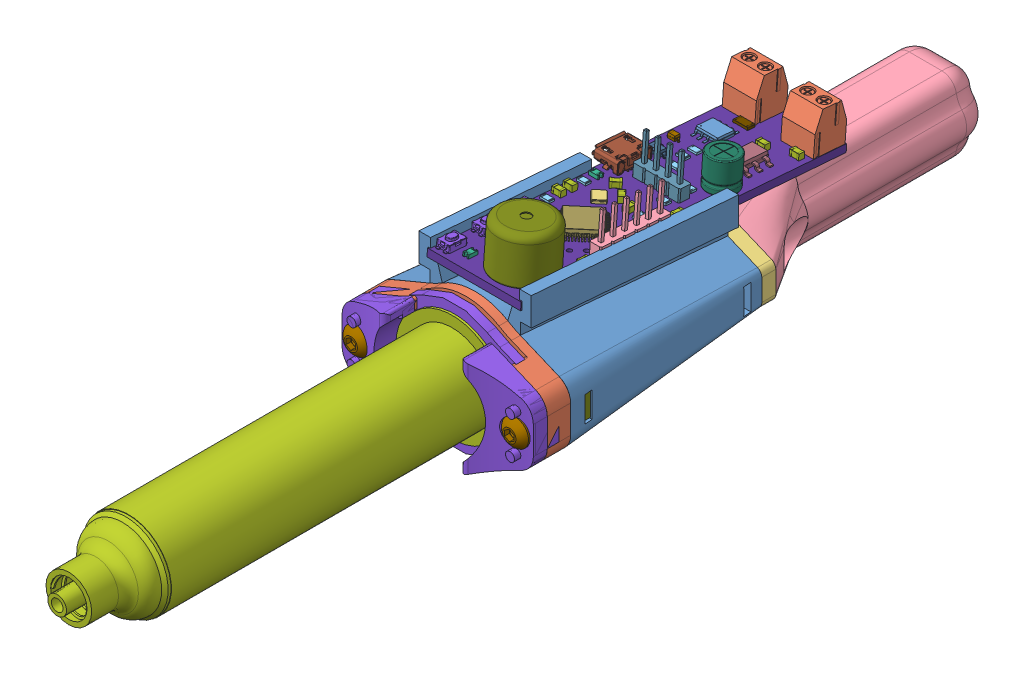
SolidWorks assembly SolderPasteMotor, configuration Default. Lengths in mm.
Overall size (41.01 39.67 192.57).
112 component instances, 35 part files, 50 mates.
Components (placement in the parent):
- ShaftCover-2: ShaftCover [Default] x (-1 0 0) z (0 0 -1) size (41.01 32.28 44.71)
- SyringeFixtureLockFlat-1: SyringeFixtureLockFlat [Default] at (0 0 2.5) size (41 27 7)
- ShaftMountFlat-1: ShaftMountFlat [Default] at (-78.4823 18.1365 -47.5) x (-1 0 0) z (0 0 1) size (34 20 3)
- TopCover-1: TopCover [Default] at (0 0 -47.5) x (1 0 0) z (0 0 -1) size (34.13 20.02 55.59)
- Piston-1: Piston [Default] at (0 0 -37.1906) size (11.9 11.9 56.85)
- Matice M4-1: Matice M4 [Matice M4] at (0 0 -23.8906) x (0.866025 -0.5 0) z (0 0 1) size (7 8.08 3.2)
- Syringe-1: Syringe [Default] at (0 0 1.9) size (30 23 87.7)
- SyringeFixtureTube-2: SyringeFixtureTube [Default] at (0 0 5) size (41 27 9.14)
- SyringeFixtureTube-3: SyringeFixtureTube [Default] at (0 0 5) x (-1 0 0) z (0 0 1) size (41 27 9.14)
- SroubM3x16pulkulata-1: SroubM3x16pulkulata [SroubM3x16pulkulata] at (17 0 9.65) x (0 0 -1) z (1 0 0) size (17.65 5.7 5.7)
- SroubM3x16pulkulata-2: SroubM3x16pulkulata [SroubM3x16pulkulata] at (-17 0 9.65) x (0 0 -1) z (1 0 0) size (17.65 5.7 5.7)
- SroubM3x16pulkulata-3: SroubM3x16pulkulata [SroubM3x16pulkulata] at (12 0 -50.65) x (0 0 1) z (-1 0 0) size (17.65 5.7 5.7)
- SroubM3x16pulkulata-4: SroubM3x16pulkulata [SroubM3x16pulkulata] at (-12 0 -50.65) x (0 0 1) z (-1 0 0) size (17.65 5.7 5.7)
- PistonHolder-1: PistonHolder [Default] at (0 0 11.3094) x (-0.337663 -0.941267 0) z (0 0 1) size (15 15 34.7)
- SyringePiston-1: SyringePiston [Default] at (0 0 30.4574) x (-0.941267 0.337663 0) z (0 0 1) size (15.7 15.7 17.5)
- MotorGearBox-1: MotorGearBox [Default] at (0 0 -95.3) x (0 -1 0) z (0 0 1) size (12.05 11.9 84.89) (flexible)
  - Motor-1: Motor [Default] at origin size (12 10 32.2)
  - GearBox-1: GearBox [Default] at (0 0 14) size (12.05 10.05 9.8)
  - Coupling-1: Coupling [Default] at (0 0 23.8) x (0.380785 0.924664 0) z (0 0 1) size (9 9 20)
  - ThreadRod-1: ThreadRod [Default] at (0 0 33.8) x (0.380785 0.924664 0) z (0 0 1) size (4.06 4.64 71.05)
- Matice M3 Ctverec-1: Matice M3 Ctverec [Default] at (17 0 -5.3) size (5.5 5.5 2)
- Matice M3 Ctverec-2: Matice M3 Ctverec [Default] at (-17 0 -3.3) x (-1 0 0) z (0 0 -1) size (5.5 5.5 2)
- Matice M3 Ctverec-3: Matice M3 Ctverec [Default] at (12 0 -42) size (5.5 5.5 2)
- Matice M3 Ctverec-4: Matice M3 Ctverec [Default] at (-12 0 -40) x (-1 0 0) z (0 0 -1) size (5.5 5.5 2)
- AxialniLozisko_F4-10_10x4x4-1: AxialniLozisko_F4-10_10x4x4 [AxialniLozisko_F6-12_12x6x4.5] at (0 0 -49.5) x (0 0 -1) z (0.989026 -0.147744 0) size (4 10 10)
- AxialniLozisko_F4-10_10x4x4-3: AxialniLozisko_F4-10_10x4x4 [AxialniLozisko_F6-12_12x6x4.5] at (0 0 -42.5) x (0 0 -1) z (0.966633 0.256167 0) size (4 10 10)
- Matice M4-2: Matice M4 [Matice M4] at (0 0 -37.3) x (0.702576 -0.711608 0) z (0 0 1) size (7 8.08 3.2)
- SPD_DC_MotorHBridge-1: SPD_DC_MotorHBridge [Default] at (-10.016 15.0227 0.2892) x (0 -0.078408 -0.996921) z (0 0.996921 -0.078408) size (70.04 21.75 12.53)
  - SPD_DC_MotorHBridge.step-1: SPD_DC_MotorHBridge.step [Default] at origin size (70.04 21.75 12.53)
    - R_1206_3216Metric.step-1: R_1206_3216Metric.step [Default] at (61.7855 -6.223 1.65) x (0 -1 0) z (0 0 1) size (3.2 1.6 0.55)
      - SOLID.step-1: SOLID.step [Default] at origin size (3.2 1.6 0.55)
    - HSOP-8-1EP_3.9x4.9mm_P1.27mm_EP2.41x3.1mm.step-1: HSOP-8-1EP_3.9x4.9mm_P1.27mm_EP2.41x3.1mm.step [Default] at (56.515 -5.2705 1.65) size (6.3 4.9 1.1)
      - SOLID-0.step-1: SOLID-0.step [Default] at origin size (6.3 4.9 1.1)
    - Screw_Terminal_Block_3.5mm_Blue_2-way.step-1: Screw_Terminal_Block_3.5mm_Blue_2-way.step [Default] at (66.294 -3.965 1.65) x (0 1 0) z (1 0 0) size (7.3 10.4 6.8)
      - COMPOUND.step-1: COMPOUND.step [Default] at origin size (7.3 10.4 6.8)
    - Crystal_SMD_SeikoEpson_TSX3225-4Pin_3.2x2.5mm_HandSoldering.step-1: Crystal_SMD_SeikoEpson_TSX3225-4Pin_3.2x2.5mm_HandSoldering.step [Default] at (29.972 -6.858 1.65) x (0.707107 0.707107 0) z (0 0 1) size (3.2 2.5 0.64)
      - SOLID-1.step-1: SOLID-1.step [Default] at origin size (3.2 2.5 0.64)
    - PinHeader_1x06_P2.54mm_Vertical.step-1: PinHeader_1x06_P2.54mm_Vertical.step [Default] at (31.242 -18.4912 1.65) x (0 -1 0) z (0 0 1) size (2.54 15.24 11.54)
      - SOLID-2.step-1: SOLID-2.step [Default] at origin size (2.54 15.24 11.54)
    - R_0805_2012Metric.step-1: R_0805_2012Metric.step [Default] at (31.496 -2.0828 1.65) x (0 1 0) z (0 0 1) size (2 1.2 0.45)
      - SOLID-3.step-1: SOLID-3.step [Default] at origin size (2 1.2 0.45)
    - D_0805_2012Metric.step-1: D_0805_2012Metric.step [Default] at (34.1376 -2.0828 1.65) x (0 1 0) z (0 0 1) size (2 1.27 0.8)
      - SOLID-4.step-1: SOLID-4.step [Default] at origin size (2 1.27 0.8)
    - R_0805_2012Metric.step-2: R_0805_2012Metric.step [Default] at (8.2804 -5.7912 1.65) x (-1 0 0) z (0 0 1) size (2 1.2 0.45)
      - SOLID-3.step-1: SOLID-3.step [Default] at origin size (2 1.2 0.45)
    - D_0805_2012Metric.step-2: D_0805_2012Metric.step [Default] at (3.4036 -5.7404 1.65) size (2 1.27 0.8)
      - SOLID-4.step-1: SOLID-4.step [Default] at origin size (2 1.27 0.8)
    - R_0805_2012Metric.step-3: R_0805_2012Metric.step [Default] at (23.622 -2.0828 1.65) x (0 -1 0) z (0 0 1) size (2 1.2 0.45)
      - SOLID-3.step-1: SOLID-3.step [Default] at origin size (2 1.2 0.45)
    - R_0805_2012Metric.step-4: R_0805_2012Metric.step [Default] at (42.5196 -8.0264 1.65) x (0 1 0) z (0 0 1) size (2 1.2 0.45)
      - SOLID-3.step-1: SOLID-3.step [Default] at origin size (2 1.2 0.45)
    - R_0805_2012Metric.step-5: R_0805_2012Metric.step [Default] at (45.1612 -8.0264 1.65) x (0 1 0) z (0 0 1) size (2 1.2 0.45)
      - SOLID-3.step-1: SOLID-3.step [Default] at origin size (2 1.2 0.45)
    - R_0805_2012Metric.step-6: R_0805_2012Metric.step [Default] at (42.2656 -13.97 1.65) x (0 1 0) z (0 0 1) size (2 1.2 0.45)
      - SOLID-3.step-1: SOLID-3.step [Default] at origin size (2 1.2 0.45)
    - R_0805_2012Metric.step-7: R_0805_2012Metric.step [Default] at (36.83 -13.97 1.65) x (0 1 0) z (0 0 1) size (2 1.2 0.45)
      - SOLID-3.step-1: SOLID-3.step [Default] at origin size (2 1.2 0.45)
    - R_0805_2012Metric.step-8: R_0805_2012Metric.step [Default] at (30.8864 -14.6812 1.65) size (2 1.2 0.45)
      - SOLID-3.step-1: SOLID-3.step [Default] at origin size (2 1.2 0.45)
    - R_0805_2012Metric.step-9: R_0805_2012Metric.step [Default] at (15.0876 -11.1252 1.65) x (0 -1 0) z (0 0 1) size (2 1.2 0.45)
      - SOLID-3.step-1: SOLID-3.step [Default] at origin size (2 1.2 0.45)
    - R_0805_2012Metric.step-10: R_0805_2012Metric.step [Default] at (50.6476 -6.8072 1.65) x (0 1 0) z (0 0 1) size (2 1.2 0.45)
      - SOLID-3.step-1: SOLID-3.step [Default] at origin size (2 1.2 0.45)
    - R_0805_2012Metric.step-11: R_0805_2012Metric.step [Default] at (48.1584 -6.7564 1.65) x (0 -1 0) z (0 0 1) size (2 1.2 0.45)
      - SOLID-3.step-1: SOLID-3.step [Default] at origin size (2 1.2 0.45)
    - C_0805_2012Metric.step-1: C_0805_2012Metric.step [Default] at (26.1112 -2.0828 1.65) x (0 -1 0) z (0 0 1) size (2 1.25 1.25)
      - SOLID-5.step-1: SOLID-5.step [Default] at origin size (2 1.25 1.25)
    - C_0805_2012Metric.step-2: C_0805_2012Metric.step [Default] at (28.5496 -2.0828 1.65) x (0 -1 0) z (0 0 1) size (2 1.25 1.25)
      - SOLID-5.step-1: SOLID-5.step [Default] at origin size (2 1.25 1.25)
    - C_0805_2012Metric.step-3: C_0805_2012Metric.step [Default] at (30.9372 -12.446 1.65) size (2 1.25 1.25)
      - SOLID-5.step-1: SOLID-5.step [Default] at origin size (2 1.25 1.25)
    - C_0805_2012Metric.step-4: C_0805_2012Metric.step [Default] at (15.0876 -6.8072 1.65) x (0 1 0) z (0 0 1) size (2 1.25 1.25)
      - SOLID-5.step-1: SOLID-5.step [Default] at origin size (2 1.25 1.25)
    - C_0805_2012Metric.step-5: C_0805_2012Metric.step [Default] at (59.2836 -12.7508 1.65) x (0 -1 0) z (0 0 1) size (2 1.25 1.25)
      - SOLID-5.step-1: SOLID-5.step [Default] at origin size (2 1.25 1.25)
    - C_0805_2012Metric.step-6: C_0805_2012Metric.step [Default] at (35.2552 -18.4912 1.65) size (2 1.25 1.25)
      - SOLID-5.step-1: SOLID-5.step [Default] at origin size (2 1.25 1.25)
    - C_0805_2012Metric.step-7: C_0805_2012Metric.step [Default] at (61.4172 -17.9324 1.65) x (0 1 0) z (0 0 1) size (2 1.25 1.25)
      - SOLID-5.step-1: SOLID-5.step [Default] at origin size (2 1.25 1.25)
    - C_0805_2012Metric.step-8: C_0805_2012Metric.step [Default] at (14.6304 -18.8468 1.65) x (-1 0 0) z (0 0 1) size (2 1.25 1.25)
      - SOLID-5.step-1: SOLID-5.step [Default] at origin size (2 1.25 1.25)
    - C_0805_2012Metric.step-9: C_0805_2012Metric.step [Default] at (34.29 -6.096 1.65) x (0.707107 -0.707107 0) z (0 0 1) size (2 1.25 1.25)
      - SOLID-5.step-1: SOLID-5.step [Default] at origin size (2 1.25 1.25)
    - C_0805_2012Metric.step-10: C_0805_2012Metric.step [Default] at (32.258 -9.398 1.65) x (0.707107 0.707107 0) z (0 0 1) size (2 1.25 1.25)
      - SOLID-5.step-1: SOLID-5.step [Default] at origin size (2 1.25 1.25)
    - KMR231NGLFS.step-1: KMR231NGLFS.step [Default] at (3.1496 -1.9685 1.65) x (-1 0 0) z (0 1 0) size (4.6 1.92 2.8)
      - SOLID-6.step-1: SOLID-6.step [Default] at origin size (4.6 1.92 2.8)
    - KMR231NGLFS.step-2: KMR231NGLFS.step [Default] at (10.7188 -1.9812 1.65) x (-1 0 0) z (0 1 0) size (4.6 1.92 2.8)
      - SOLID-6.step-1: SOLID-6.step [Default] at origin size (4.6 1.92 2.8)
    - KMR231NGLFS.step-3: KMR231NGLFS.step [Default] at (18.2372 -1.9812 1.65) x (-1 0 0) z (0 1 0) size (4.6 1.92 2.8)
      - SOLID-6.step-1: SOLID-6.step [Default] at origin size (4.6 1.92 2.8)
    - D_SOD-323.step-1: D_SOD-323.step [Default] at (49.53 -11.43 1.65) x (0 1 0) z (0 0 1) size (2.5 1.25 1.1)
      - SOLID-7.step-1: SOLID-7.step [Default] at origin size (2.5 1.25 1.1)
    - D_SOD-323.step-2: D_SOD-323.step [Default] at (50.673 -2.2225 1.65) x (0 -1 0) z (0 0 1) size (2.5 1.25 1.1)
      - SOLID-7.step-1: SOLID-7.step [Default] at origin size (2.5 1.25 1.1)
    - D_SOD-123.step-1: D_SOD-123.step [Default] at (45.8724 -3.4036 1.65) x (0 -1 0) z (0 0 1) size (3.8 1.6 1.25)
      - SOLID-8.step-1: SOLID-8.step [Default] at origin size (3.8 1.6 1.25)
    - USB_Micro-B_Amphenol_10118193-0001LF_Horizontal.step-1: USB_Micro-B_Amphenol_10118193-0001LF_Horizontal.step [Default] at (138.1935 -4.547 1.3) x (-1 0 0) z (0 1 0) size (7.87 3.61 5.71)
      - COMPOUND-9.step-1: COMPOUND-9.step [Default] at origin size (7.87 3.61 5.71)
    - LQFP-48_7x7mm_P0.5mm.step-1: LQFP-48_7x7mm_P0.5mm.step [Default] at (22.5552 -10.9855 1.65) x (-0.707107 -0.707107 0) z (0 0 1) size (9 9 1.5)
      - SOLID-10.step-1: SOLID-10.step [Default] at origin size (9 9 1.5)
    - Screw_Terminal_Block_3.5mm_Blue_2-way.step-2: Screw_Terminal_Block_3.5mm_Blue_2-way.step [Default] at (66.294 -16.538 1.65) x (0 1 0) z (1 0 0) size (7.3 10.4 6.8)
      - COMPOUND.step-1: COMPOUND.step [Default] at origin size (7.3 10.4 6.8)
    - SOT-223.step-1: SOT-223.step [Default] at (54.2036 -13.97 1.65) x (0 1 0) z (0 0 1) size (7 6.5 1.7)
      - SOLID-11.step-1: SOLID-11.step [Default] at origin size (7 6.5 1.7)
    - PinHeader_1x04_P2.54mm_Vertical.step-1: PinHeader_1x04_P2.54mm_Vertical.step [Default] at (39.5224 -14.478 1.65) x (-1 0 0) z (0 0 1) size (2.54 10.16 11.54)
      - SOLID-12.step-1: SOLID-12.step [Default] at origin size (2.54 10.16 11.54)
    - CP_Radial_D6.3mm_P2.50mm.step-1: CP_Radial_D6.3mm_P2.50mm.step [Default] at (45.5568 -16.3576 1.65) size (7.78 8.05 8.3)
      - SOLID-13.step-1: SOLID-13.step [Default] at origin size (7.78 8.05 8.3)
    - Buzzer_12x9.5RM7.6.step-1: Buzzer_12x9.5RM7.6.step [Default] at (10.668 -13.589 1.65) x (-1 0 0) z (0 0 1) size (12 12 12.53)
      - SOLID-14.step-1: SOLID-14.step [Default] at origin size (12 12 12.53)
    - COMPOUND-15.step-1: COMPOUND-15.step [Default] at origin size (70.04 20.07 1.6)
Mates (geometry in assembly coordinates):
- Rovnoběžná1: parallel anti-aligned: plane of Piston-1 through (2.0207 3.5 -23.8906) normal (-0.866025 -0.5 0); plane of Matice M4-1 through (4.0415 0 -27.0906) normal (0.866025 0.5 0)
- Sjednocená9: coincident anti-aligned: plane of Piston-1 through (0 0 -23.8906) normal (0 0 -1); plane of Matice M4-1 through (-6.0622 3.5 -23.8906) normal (0 0 1)
- Sjednocená11: coincident anti-aligned: plane of SyringeFixtureLockFlat-1 through (16.5 -2.982 0) normal (0 0 -1); plane of ShaftCover-2 through (16.5 3 0) normal (0 0 1)
- Soustředná164: concentric aligned: cylinder of ShaftMountFlat-1 through (0 0 -47.5) axis (0 0 1) radius 2.25; cylinder of ShaftCover-2 through (0 0 -14) axis (0 0 1) radius 8.75
- Soustředná165: concentric anti-aligned: cylinder of ShaftMountFlat-1 through (12 0 -47.5) axis (0 0 1) radius 1.8; cylinder of ShaftCover-2 through (12 0 -29.5) axis (0 0 -1) radius 1.8
- Sjednocená12: coincident anti-aligned: plane of ShaftMountFlat-1 through (0 0 -44.5) normal (0 0 1); plane of ShaftCover-2 through (0 0 -44.5) normal (0 0 -1)
- Sjednocená13: coincident anti-aligned: plane of ShaftMountFlat-1 through (0 0 -47.5) normal (0 0 -1); plane of TopCover-1 through (0 0 -47.5) normal (0 0 1)
- Soustředná167: concentric aligned: cylinder of ShaftMountFlat-1 through (12 0 -47.5) axis (0 0 1) radius 1.8; cylinder of TopCover-1 through (12 0 -96.5098) axis (0 0 1) radius 1.8
- Sjednocená14: coincident anti-aligned: plane of SyringeFixtureLockFlat-1 through (0 0 1.9) normal (0 0 1); plane of Syringe-1 through (9.3374 -9.75 1.9) normal (0 0 -1)
- Soustředná169: concentric anti-aligned: cylinder of ShaftCover-2 through (0 0 -14) axis (0 0 1) radius 8.75; cylinder of Syringe-1 through (0 0 74.3) axis (0 0 -1) radius 9.2
- Soustředná175: concentric anti-aligned: cylinder of ShaftCover-2 through (17 0 -14) axis (0 0 1) radius 1.8; cylinder of SyringeFixtureLockFlat-1 through (17 0 5) axis (0 0 -1) radius 1.8
- Soustředná176: concentric anti-aligned: cylinder of ShaftCover-2 through (-17 0 -14) axis (0 0 1) radius 1.8; cylinder of SyringeFixtureLockFlat-1 through (-17 0 5) axis (0 0 -1) radius 1.8
- Soustředná178: concentric aligned: cylinder of ShaftMountFlat-1 through (-12 0 -47.5) axis (0 0 1) radius 1.8; cylinder of TopCover-1 through (-12 0 -96.5098) axis (0 0 1) radius 1.8
- Mezní úhel1: limit planar angle = 0 rad anti-aligned: plane of Syringe-1 through (9.3374 -7.75 4.9) normal (0 -1 0); plane of SyringeFixtureLockFlat-1 through (9.3374 -7.75 1.9) normal (0 1 0)
- Sjednocená16: coincident anti-aligned: plane of SyringeFixtureLockFlat-1 through (16.5 -2.982 5) normal (0 0 1); plane of SyringeFixtureTube-2 through (16.5 2.982 5) normal (0 0 -1)
- Soustředná179: concentric aligned: cylinder of SyringeFixtureLockFlat-1 through (17 0 5) axis (0 0 -1) radius 1.8; cylinder of SyringeFixtureTube-2 through (17 0 12) axis (0 0 -1) radius 1.8
- Soustředná1821: concentric anti-aligned: cylinder of SyringeFixtureTube-2 through (17 0 12) axis (0 0 -1) radius 1.8; cylinder of SroubM3x16pulkulata-1 through (17 0 9.65) axis (0 0 1) radius 2.85
- Sjednocená241: coincident anti-aligned: plane of SyringeFixtureTube-2 through (17 0 8) normal (0 0 1); plane of SroubM3x16pulkulata-1 through (17 1.5 8) normal (0 0 -1)
- Soustředná1831: concentric aligned: cylinder of TopCover-1 through (12 0 -49) axis (0 0 -1) radius 3; cylinder of SroubM3x16pulkulata-3 through (12 0 -50.65) axis (0 0 -1) radius 2.85
- Sjednocená251: coincident anti-aligned: plane of TopCover-1 through (12 0 -49) normal (0 0 -1); plane of SroubM3x16pulkulata-3 through (12 1.5 -49) normal (0 0 1)
- Soustředná185: concentric anti-aligned: cylinder of PistonHolder-1 through (0 0 11.3094) axis (0 0 1) radius 2.1; cylinder of SyringePiston-1 through (0 0 47.9584) axis (0 0 -1) radius 1
- Rovnoběžná4: parallel anti-aligned: plane of PistonHolder-1 through (-0.4834 0.5984 39.4594) normal (-0.337663 -0.941267 0); plane of SyringePiston-1 through (0.1351 0.3765 47.9594) normal (0.337663 0.941267 0)
- Sjednocená28: coincident aligned: circle of PistonHolder-1; circle of SyringePiston-1
- Sjednocená30: coincident aligned: plane of SyringeFixtureLockFlat-1 through (20.5 3 5) normal (1 0 0); plane of SyringeFixtureTube-2 through (20.5 3 12) normal (1 0 0)
- Mezní vzdálenost3: limit distance = 38.6426 mm aligned: plane of Syringe-1 through (-4.9 0 78.1) normal (0 0 -1); plane of SyringePiston-1 through (0 0 39.4574) normal (0 0 -1)
- Rovnoběžná6: parallel anti-aligned: plane of SyringeFixtureLockFlat-1 through (-4.65 6.2 0) normal (0 -1 0); plane of Piston-1 through (5 5.95 11.3094) normal (0 1 0)
- Šroub1: screw = 1.5 mm anti-aligned: cylinder of Piston-1 through (0 0 11.3094) axis (0 0 -1) radius 7.5; circle of PistonHolder-1
- Vystředění3: width anti-aligned: plane of TopCover-1 through (-5.25 -6.25 -97) normal (1 0 0); plane of TopCover-1 through (5.25 -6.25 -97) normal (-1 0 0); plane of MotorGearBox-1/Motor-1 through (-5 3.35 -81.3) normal (-1 0 0); plane of MotorGearBox-1/Motor-1 through (5 3.35 -81.3) normal (1 0 0)
- Vystředění4: width anti-aligned: plane of TopCover-1 through (5.25 6.25 -97) normal (0 -1 0); plane of TopCover-1 through (5.25 -6.25 -97) normal (0 1 0); plane of MotorGearBox-1/GearBox-1 through (5.025 6.025 -72.3) normal (0 1 0); plane of MotorGearBox-1/GearBox-1 through (5.025 -6.025 -72.3) normal (0 -1 0)
- Soustředná1832: concentric aligned: cylinder of Piston-1 through (0 0 -16.298) axis (0 0 -1) radius 2.4; cylinder of MotorGearBox-1/Coupling-1 through (0 0 -51.5) axis (0 0 -1) radius 4.5
- Šroub2: screw = 0.7 anti-aligned: cylinder of PistonHolder-1 through (0 0 46.3094) axis (0 0 -1) radius 7.5; circle of MotorGearBox-1/ThreadRod-1
- Sjednocená253: coincident anti-aligned: plane of Piston-1 through (0 0 11.3094) normal (0 0 1); plane of PistonHolder-1 through (0 0 11.3094) normal (0 0 -1)
- Soustředná1833: concentric aligned: cylinder of ShaftCover-2 through (17 0 -14) axis (0 0 1) radius 1.8; cylinder of Matice M3 Ctverec-1 through (17 0 -5.3) axis (0 0 1) radius 1.5
- Sjednocená254: coincident anti-aligned: plane of ShaftCover-2 through (0 0 -3.3) normal (0 0 -1); plane of Matice M3 Ctverec-1 through (17 0 -3.3) normal (0 0 1)
- Rovnoběžná7: parallel anti-aligned: plane of ShaftCover-2 through (19.75 2.75 -3.3) normal (0 -1 0); plane of Matice M3 Ctverec-1 through (14.25 2.75 -3.3) normal (0 1 0)
- Rovnoběžná8: parallel anti-aligned: plane of ShaftCover-2 through (14.75 2.75 -40.3) normal (0 -1 0); plane of Matice M3 Ctverec-3 through (9.25 2.75 -40) normal (0 1 0)
- Sjednocená255: coincident anti-aligned: plane of ShaftCover-2 through (0 0 -42) normal (0 0 1); plane of Matice M3 Ctverec-3 through (12 0 -42) normal (0 0 -1)
- Soustředná1834: concentric anti-aligned: cylinder of ShaftCover-2 through (12 0 -29.5) axis (0 0 -1) radius 1.8; cylinder of Matice M3 Ctverec-3 through (12 0 -42) axis (0 0 1) radius 1.5
- Soustředná1835: concentric anti-aligned: cylinder of ShaftMountFlat-1 through (0 0 -47.5) axis (0 0 1) radius 2.25; cylinder of MotorGearBox-1/Coupling-1 through (0 0 -51.5) axis (0 0 -1) radius 4.5
- Soustředná1836: concentric aligned: cylinder of MotorGearBox-1/Coupling-1 through (0 0 -51.5) axis (0 0 -1) radius 4.5; cylinder of AxialniLozisko_F4-10_10x4x4-1 through (0 0 -14.575) axis (0 0 -1) radius 2
- Sjednocená256: coincident anti-aligned: plane of ShaftMountFlat-1 through (0 0 -47.5) normal (0 0 -1); plane of AxialniLozisko_F4-10_10x4x4-1 through (0.3398 2.2748 -47.5) normal (0 0 1)
- Sjednocená259: coincident anti-aligned: plane of MotorGearBox-1/Coupling-1 through (0 0 -51.5) normal (0 0 1); plane of AxialniLozisko_F4-10_10x4x4-1 through (0.3398 2.2748 -51.5) normal (0 0 -1)
- Soustředná1837: concentric anti-aligned: cylinder of MotorGearBox-1/Coupling-1 through (0 0 -51.5) axis (0 0 -1) radius 4.5; cylinder of AxialniLozisko_F4-10_10x4x4-3 through (0 0 -77.425) axis (0 0 1) radius 2
- Sjednocená260: coincident anti-aligned: plane of ShaftMountFlat-1 through (0 0 -44.5) normal (0 0 1); plane of AxialniLozisko_F4-10_10x4x4-3 through (-0.5892 2.2233 -44.5) normal (0 0 -1)
- Soustředná1838: concentric anti-aligned: cylinder of MotorGearBox-1/Coupling-1 through (0 0 -51.5) axis (0 0 -1) radius 4.5; cylinder of Matice M4-2 through (0 0 -40.5) axis (0 0 1) radius 1.65
- Sjednocená261: coincident anti-aligned: plane of AxialniLozisko_F4-10_10x4x4-3 through (-0.5892 2.2233 -40.5) normal (0 0 1); plane of Matice M4-2 through (-4.918 4.9813 -40.5) normal (0 0 -1)
- Sjednocená274: coincident anti-aligned: plane of ShaftCover-2 through (8.05 14.9999 0) normal (0 0.996921 -0.078408); plane of SPD_DC_MotorHBridge-1/SPD_DC_MotorHBridge.step-1/COMPOUND-15.step-1 through (0.017 12.2768 -34.6232) normal (0 -0.996921 0.078408)
- Sjednocená275: coincident anti-aligned: plane of ShaftCover-2 through (10.05 14.9999 0) normal (-1 0 0); plane of SPD_DC_MotorHBridge-1/SPD_DC_MotorHBridge.step-1/COMPOUND-15.step-1 through (10.05 9.5309 -69.5357) normal (1 0 0)
- Sjednocená277: coincident: line of ShaftCover-2 through (9.55 18.6999 0) axis (1 0 0); plane of SPD_DC_MotorHBridge-1/SPD_DC_MotorHBridge.step-1/COMPOUND-15.step-1 through (10.05 15.0227 0.2892) normal (0 0.078408 0.996921)
- Mezní vzdálenost5: limit distance = 9.3094 mm anti-aligned: plane of ShaftMountFlat-1 through (0 0 -44.5) normal (0 0 1); plane of Piston-1 through (0 0 -35.1906) normal (0 0 -1)
